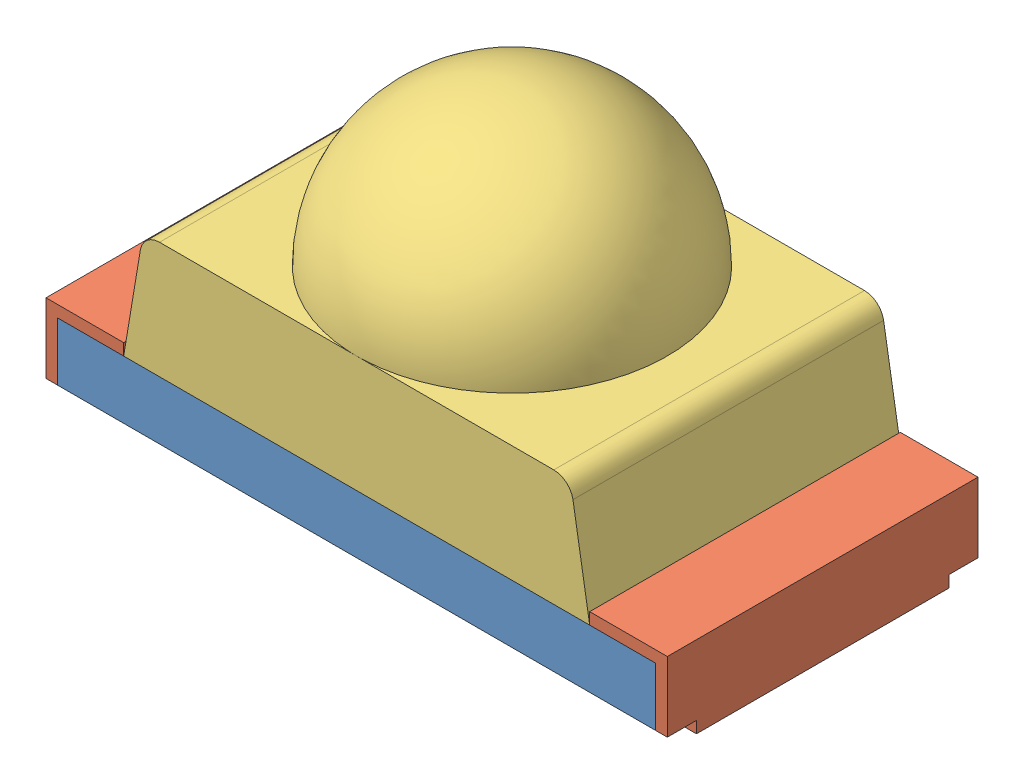
SolidWorks assembly LED0603Y, configuration Default. Lengths in mm.
Overall size (1.6 0.88 0.8).
4 component instances, 3 part files, 9 mates.
Components (placement in the parent):
- LED0603-substrate-1: LED0603-substrate [Default] at (0 0.03 0) size (1.54 0.15 0.8)
- LED0603-clip-1: LED0603-clip [Default] at (-0.8 0.105 0) x (1 0 0) z (0 1 0) size (0.3 0.8 0.21)
- LED0603-clip-2: LED0603-clip [Default] at (0.8 0.105 0) x (-1 0 0) z (0 1 0) size (0.3 0.8 0.21)
- LED0603-lens-1: LED0603-lens [Default] at (0 0.18 0) size (1.2 0.7 0.8)
Mates (geometry in assembly coordinates):
- Coincident1: coincident aligned: plane of LED0603-substrate-1 through (0 0.03 0) normal (1 0 0)
- Coincident2: coincident aligned: plane of LED0603-substrate-1 through (0 0.03 0) normal (0 0 1)
- Distance1: distance = 0.03 mm aligned: plane of LED0603-substrate-1 through (0 0.03 0) normal (0 1 0)
- Coincident4: coincident anti-aligned: plane of LED0603-clip-1 through (-0.8 0.105 0) normal (0 0 -1)
- Coincident5: coincident anti-aligned: plane of LED0603-substrate-1 through (0 0.03 0) normal (0 -1 0); plane of LED0603-clip-1 through (-0.5 0.03 -0.4) normal (0 1 0)
- Coincident6: coincident anti-aligned: plane of LED0603-substrate-1 through (-0.77 0.18 0.4) normal (-1 0 0); plane of LED0603-clip-1 through (-0.77 0.18 -0.4) normal (1 0 0)
- Coincident7: coincident aligned: plane of LED0603-lens-1 through (0 0.18 0) normal (0 0 1)
- Coincident8: coincident aligned: plane of LED0603-lens-1 through (0 0.18 0) normal (1 0 0)
- Coincident9: coincident anti-aligned: plane of LED0603-substrate-1 through (0 0.18 0) normal (0 1 0); plane of LED0603-lens-1 through (0 0.18 0) normal (0 -1 0)
